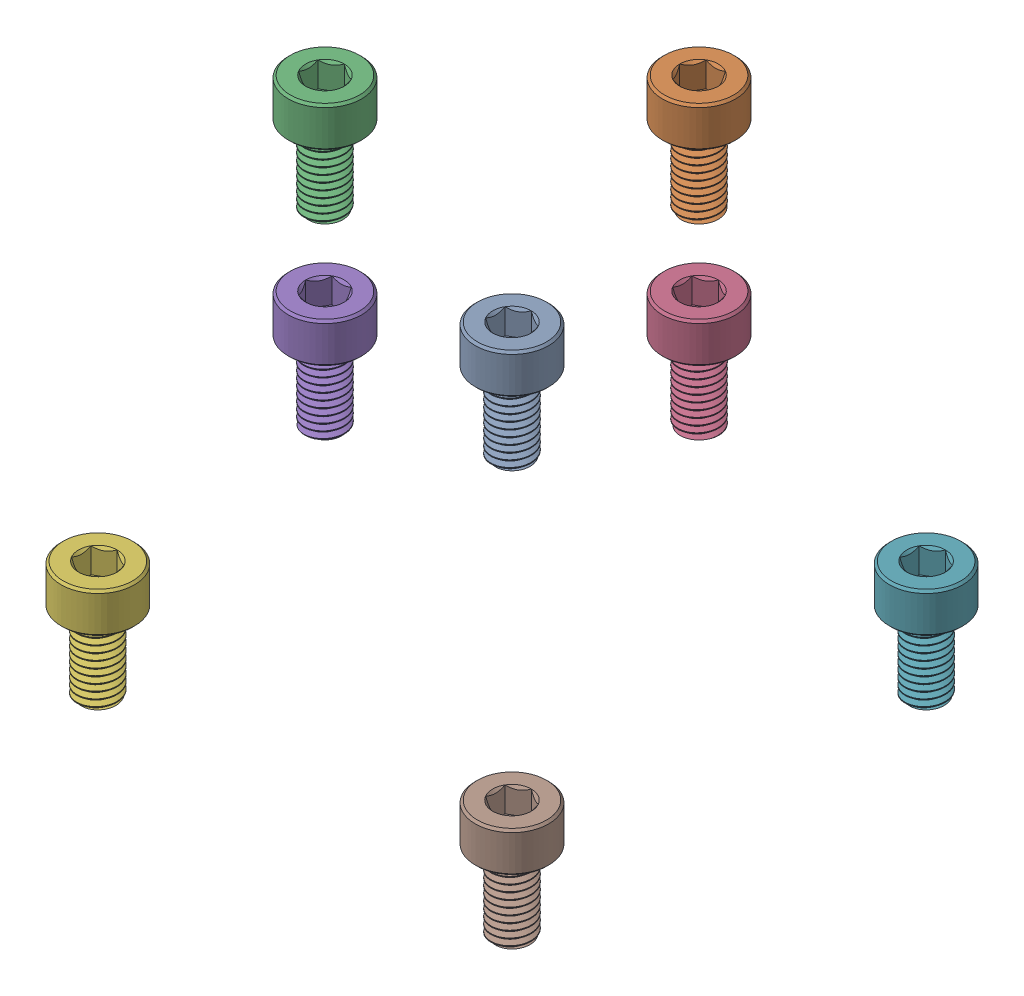
SolidWorks assembly Screws.step, configuration Default. Lengths in mm.
Overall size (36.5 33.5 36.5).
8 component instances, 1 part files, 0 mates.
Components (placement in the parent):
- M3 x 6mm.step-1: M3 x 6mm.step [Default] at (-15.5 44 -15.5) x (1 0 0) z (0 -1 0) size (5.5 5.5 9)
- M3 x 6mm.step-2: M3 x 6mm.step [Default] at (0 68.5 -14) x (0 0 1) z (0 -1 0) size (5.5 5.5 9)
- M3 x 6mm.step-3: M3 x 6mm.step [Default] at (-14 68.5 0) x (1 0 0) z (0 -1 0) size (5.5 5.5 9)
- M3 x 6mm.step-4: M3 x 6mm.step [Default] at (14 68.5 0) x (-1 0 0) z (0 -1 0) size (5.5 5.5 9)
- M3 x 6mm.step-5: M3 x 6mm.step [Default] at (0 68.5 14) x (0 0 -1) z (0 -1 0) size (5.5 5.5 9)
- M3 x 6mm.step-6: M3 x 6mm.step [Default] at (-15.5 44 15.5) x (1 0 0) z (0 -1 0) size (5.5 5.5 9)
- M3 x 6mm.step-7: M3 x 6mm.step [Default] at (15.5 44 -15.5) x (1 0 0) z (0 -1 0) size (5.5 5.5 9)
- M3 x 6mm.step-8: M3 x 6mm.step [Default] at (15.5 44 15.5) x (1 0 0) z (0 -1 0) size (5.5 5.5 9)
